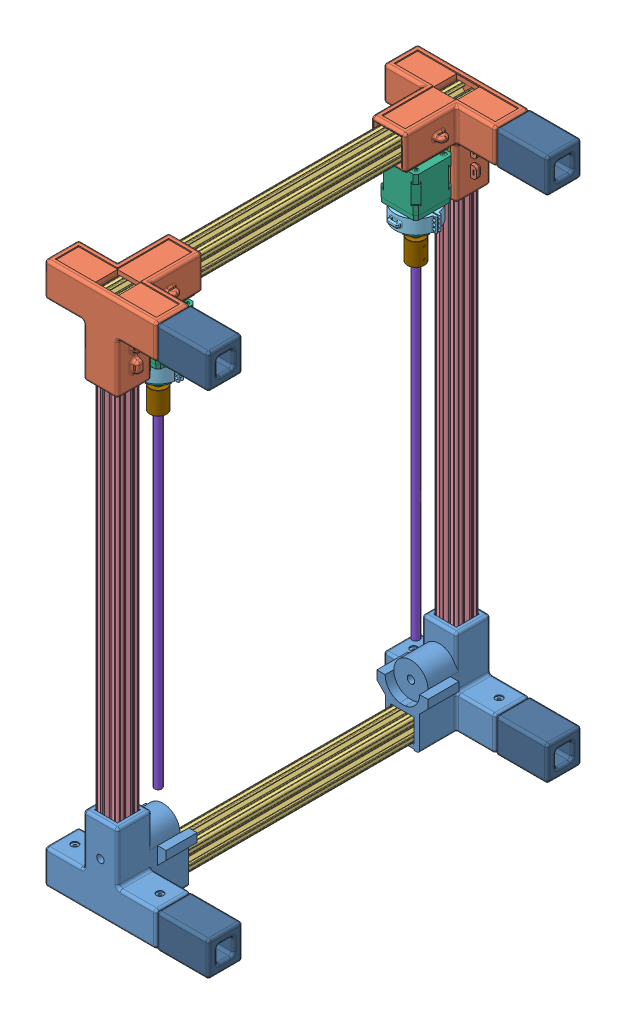
SolidWorks assembly 3PT3-Frame, configuration Default. Lengths in mm.
Overall size (183.1 628.84 416.75).
27 component instances, 10 part files, 0 mates.
Components (placement in the parent):
- MANDELBOT3PT3-1: MANDELBOT3PT3 [Default] at (128.3615 952.8135 853.6182) size (183.1 628.84 416.75)
  - 3-bottom_leftnright_courner-1: 3-bottom_leftnright_courner [Default] at (-233.6715 -850.4146 -39.4134) x (1 0 0) z (0 0 -1) size (124.9 95.25 79.43)
  - 3-bottom_leftnright_courner-2: 3-bottom_leftnright_courner [Default] at (-233.6715 -850.4146 -456.1639) x (-1 0 0) z (0 0 1) size (124.9 95.25 79.43)
  - 3-Top_leftnright_courner-1: 3-Top_leftnright_courner [Default] at (-233.6715 -282.0896 -456.1639) size (124.9 134.97 141.56)
  - 3-1010-1: 3-1010 [Default] at (-233.6715 -850.4146 -45.3824) x (-1 0 0) z (0 0 1) size (25.4 25.4 404.81)
  - 3-1010 - Copy-1: 3-1010 - Copy [Default] at (-233.6715 -294.7896 -437.1139) x (-1 0 0) z (0 1 0) size (25.4 25.4 542.92)
  - 3-1010-2: 3-1010 [Default] at (-233.6715 -282.0896 -450.1949) x (-1 0 0) z (0 0 -1) size (25.4 25.4 404.81)
  - 3-1010 - Copy-2: 3-1010 - Copy [Default] at (-233.6715 -294.7896 -58.4634) x (-1 0 0) z (0 1 0) size (25.4 25.4 542.92)
  - 3-Top_leftnright_courner-2: 3-Top_leftnright_courner [Default] at (-233.6715 -282.0896 -39.4134) x (-1 0 0) z (0 0 -1) size (124.9 134.97 141.56)
  - 3-StepperandClamp-1: 3-StepperandClamp [Default] at (-169.3666 -349.3049 -231.1482) x (0.019579 0 -0.999808) z (-0.999808 0 -0.019579) size (53.34 87.3 49.25)
    - 3-SteppermotormountNew-1: 3-SteppermotormountNew [Default] at (-128.5327 11.5427 61.6662) size (53.34 15.88 49.25)
    - 3-Nema17SW-1: 3-Nema17SW [Default] at (-128.5327 -2.8313 61.6662) x (0.999808 0 0.019579) z (0 1 0) size (42.88 42 87.3)
  - 3-Eraser-1: 3-Eraser [Default] at (-233.6715 -282.0896 -82.8474) size (25.4 51.18 6.6)
  - 3-Eraser-2: 3-Eraser [Default] at (-233.6715 -306.4736 -58.4634) x (-1 0 0) z (0 1 0) size (25.4 51.18 6.6)
  - 3-FakeLeadscrew-1: 3-FakeLeadscrew [Default] at (-233.5376 -774.7736 -103.8474) x (0.569946 0 0.821682) z (0 1 0) size (8 8 381)
  - 3-Eraser-3: 3-Eraser [Default] at (-233.6715 -306.4736 -341.8639) x (-1 0 0) z (0 1 0) size (25.4 51.18 6.6)
  - 3-Eraser-4: 3-Eraser [Default] at (-233.6715 -282.0896 -412.7299) x (-1 0 0) z (0 0 -1) size (25.4 51.18 6.6)
  - 3-StepperandClamp-2: 3-StepperandClamp [Default] at (-169.3666 -349.3049 -519.0307) x (0.019579 0 -0.999808) z (-0.999808 0 -0.019579) size (53.34 87.3 49.25)
    - 3-SteppermotormountNew-1: 3-SteppermotormountNew [Default] at (-128.5327 11.5427 61.6662) size (53.34 15.88 49.25)
    - 3-Nema17SW-1: 3-Nema17SW [Default] at (-128.5327 -2.8313 61.6662) x (0.999808 0 0.019579) z (0 1 0) size (42.88 42 87.3)
  - 3-FakeLeadscrew-3: 3-FakeLeadscrew [Default] at (-233.5376 -774.7736 -391.7299) x (0.569946 0 0.821682) z (0 1 0) size (8 8 381)
  - 3-Y-leadscrew_colles-1: 3-Y-leadscrew_colles [Default] at (-233.5376 -409.6636 -391.7299) size (18.9 25 18.9)
  - 3-Y-leadscrew_colles-2: 3-Y-leadscrew_colles [Default] at (-233.5376 -409.6636 -103.8474) x (0.605381 0 -0.795936) z (0.795936 0 0.605381) size (18.9 25 18.9)
  - 3-endExtender-1: 3-endExtender [Default] at (-214.6215 -850.4146 -58.4634) x (0 0 -1) z (0 -1 0) size (38.1 101.6 38.1)
  - 3-endExtender-2: 3-endExtender [Default] at (-214.6215 -282.0896 -58.4634) x (0 -1 0) z (0 0 1) size (38.1 101.6 38.1)
  - 3-endExtender-3: 3-endExtender [Default] at (-214.6215 -282.0896 -437.1139) x (0 -1 0) z (0 0 1) size (38.1 101.6 38.1)
  - 3-endExtender-4: 3-endExtender [Default] at (-214.6215 -850.4146 -437.1139) x (0 -1 0) z (0 0 1) size (38.1 101.6 38.1)
